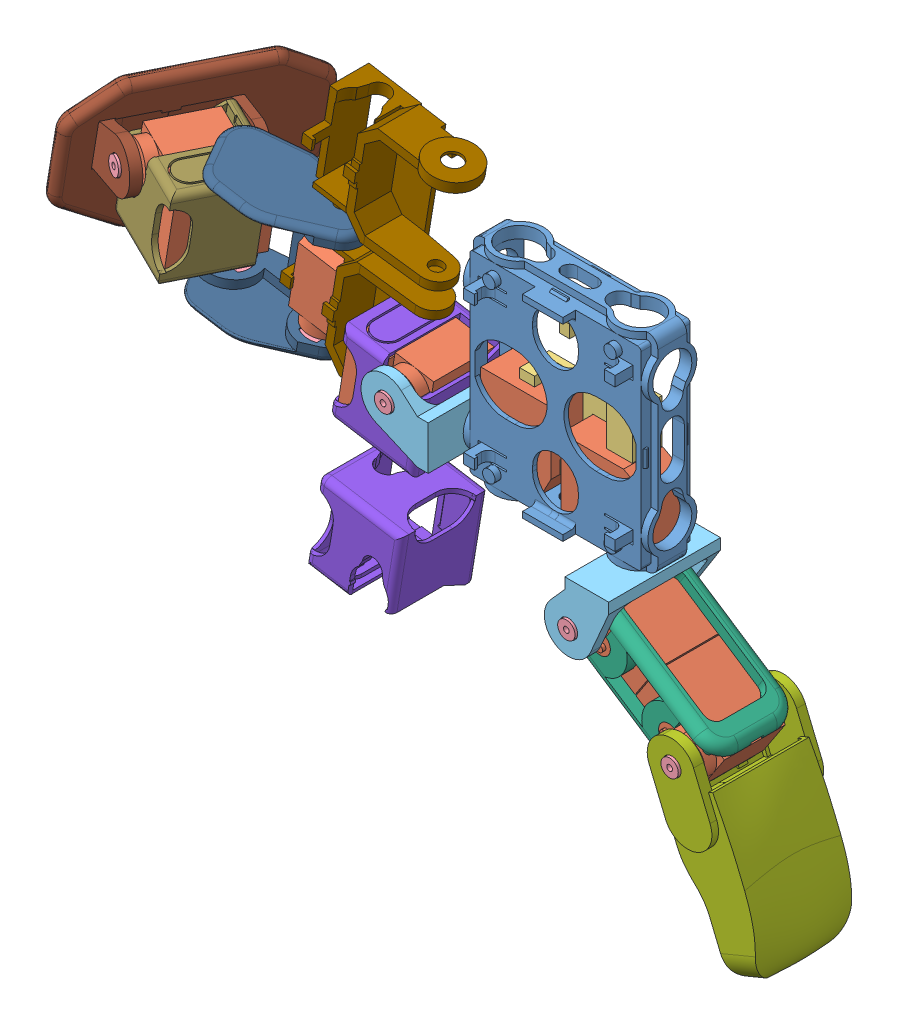
SolidWorks assembly Assem_Body, configuration ﾃﾞﾌｫﾙﾄ. Lengths in mm.
Overall size (223.32 163.88 67.55).
29 component instances, 14 part files, 74 mates.
Components (placement in the parent):
- body_middle-1: body_middle [ﾃﾞﾌｫﾙﾄ] at (-32.055 10.1 -20.8) x (0 -1 0) z (0 0 1) size (61.6 54.8 19.4)
- plen2motor_digital_metalgear-3: plen2motor_digital_metalgear [ﾃﾞﾌｫﾙﾄ] at (-11.955 -23.4 -20.8) x (1 0 0) z (0 1 0) size (23.8 11.6 27.9)
- plen2motor_digital_metalgear-4: plen2motor_digital_metalgear [ﾃﾞﾌｫﾙﾄ] at (-14.955 -18.3 -20.8) x (0 -1 0) z (1 0 0) size (23.8 11.6 27.9)
- PLEN2BaseBoard-1: PLEN2BaseBoard [ﾃﾞﾌｫﾙﾄ] at (-32.055 10.1 -19.3) x (0 -1 0) z (0 0 1) size (54 40 1.6) (hidden)
- body_rear-1: body_rear [Default] at (-39.455 -47.7 -22.3) x (0 1 0) z (0 0 -1) size (61.6 54.8 34) (hidden)
- motor_fix_body-1: motor_fix_body [ﾃﾞﾌｫﾙﾄ] at (-12.155 -23.4 -32.4) x (1 0 0) z (0 0 -1) size (33.46 40 8.8)
- servo_horn_rev1-1: servo_horn_rev1 [Default] at (0.7719 -62.1036 -11.1999) x (-1 0 0) z (0 -1 0) size (10.8 3.5 10.8)
- servo_bracket_type1-1: servo_bracket_type1 [ﾃﾞﾌｫﾙﾄ] at (-51.1552 -22.6 -29.3499) x (0 1 0) z (0 0 -1) size (93.31 19.12 33.2)
- plen2motor_digital_metalgear-5: plen2motor_digital_metalgear [ﾃﾞﾌｫﾙﾄ] at (12.7873 -76.9532 -38.8999) x (-0.835365 0.549695 0) z (0 0 -1) size (23.8 11.6 27.9)
- servo_assem_type1-1: servo_assem_type1 [ﾃﾞﾌｫﾙﾄ] at (36.1079 -85.3557 -18.0999) x (-0.835365 0.549695 0) z (0 0 -1) size (47.9 17.6 27.3)
- plen2motor_digital_metalgear-6: plen2motor_digital_metalgear [ﾃﾞﾌｫﾙﾄ] at (19.4144 -67.4279 -38.8999) x (0.835365 -0.549695 0) z (0 0 -1) size (23.8 11.6 27.9)
- hand_with_bracket-1: hand_with_bracket [ﾃﾞﾌｫﾙﾄ] at (-4.2028 -115.5264 -29.4499) x (-0.923728 -0.383049 0) z (0 0 -1) size (19.58 60.26 33.2)
- servo_horn_rev1-2: servo_horn_rev1 [Default] at (31.4298 -82.2774 -11.1999) x (-0.923728 -0.383049 0) z (0.383049 -0.923728 0) size (10.8 3.5 10.8)
- servo_bracket_type1-2: servo_bracket_type1 [ﾃﾞﾌｫﾙﾄ] at (-14.155 20.9003 -29.3499) x (1 0 0) z (0 0 -1) size (93.31 19.12 33.2)
- servo_horn_rev1-3: servo_horn_rev1 [Default] at (-53.6586 -31.0269 -11.1999) x (1 0 0) z (0 1 0) size (10.8 3.5 10.8)
- servo_assem_type2-1: servo_assem_type2 [ﾃﾞﾌｫﾙﾄ] at (-77.6577 -55.3938 -17.9888) x (0.162468 0.986714 0) z (0 0 -1) size (71.68 25.2 27.6)
- plen2motor_digital_metalgear-7: plen2motor_digital_metalgear [ﾃﾞﾌｫﾙﾄ] at (-62.3384 -48.0427 -38.8999) x (0.162468 0.986714 0) z (0 0 -1) size (23.8 11.6 27.9)
- plen2motor_digital_metalgear-8: plen2motor_digital_metalgear [ﾃﾞﾌｫﾙﾄ] at (-58.6342 -25.5457 -16.0999) x (0 0 -1) z (0.162468 0.986714 0) size (23.8 11.6 27.9)
- servo_bracket_knee-1: servo_bracket_knee [ﾃﾞﾌｫﾙﾄ] at (-49.504 -19.9541 -32.5496) x (0.162468 0.986714 0) z (0 0 -1) size (71 42.95 18.19)
- servo_horn_rev1-4: servo_horn_rev1 [Default] at (-68.8575 -51.9353 -34.2999) x (0.986714 -0.162468 0) z (0 0 1) size (10.8 3.5 10.8)
- plen2motor_digital_metalgear-9: plen2motor_digital_metalgear [ﾃﾞﾌｫﾙﾄ] at (-97.659 -18.8159 -52.7998) x (0 0 1) z (0.162468 0.986714 0) size (23.8 11.6 27.9)
- servo_bracket_shin-1: servo_bracket_shin [ﾃﾞﾌｫﾙﾄ] at (-49.3565 -19.6749 -32.8498) x (0.162468 0.986714 0) z (0 0 -1) size (74.63 42.87 25.65)
- servo_horn_rev1-5: servo_horn_rev1 [Default] at (-96.4365 -47.0902 -34.5998) x (0.986714 -0.162468 0) z (0 0 1) size (10.8 3.5 10.8)
- servo_horn_rev1-6: servo_horn_rev1 [Default] at (-124.1627 -42.5249 -34.6001) x (0.986714 -0.162468 0) z (0 0 1) size (10.8 3.5 10.8)
- plen2motor_digital_metalgear-10: plen2motor_digital_metalgear [ﾃﾞﾌｫﾙﾄ] at (-137.5668 -35.3519 -45.408) x (0.162468 0.986714 0) z (0.371194 -0.061119 -0.926542) size (23.8 11.6 27.9)
- plen2motor_digital_metalgear-11: plen2motor_digital_metalgear [ﾃﾞﾌｫﾙﾄ] at (-121.1155 -14.9537 -15.5552) x (0.371194 -0.061119 -0.926542) z (0.162468 0.986714 0) size (23.8 11.6 27.9)
- foot_with_bracket-1: foot_with_bracket [ﾃﾞﾌｫﾙﾄ] at (-55.2342 -17.2884 -5.1428) x (0.162468 0.986714 0) z (0.371194 -0.061119 -0.926542) size (42.36 22.25 63.87)
- servo_horn_rev1-7: servo_horn_rev1 [Default] at (-139.5894 -16.5738 -17.5608) x (0.162468 0.986714 0) z (-0.914231 0.150534 -0.376192) size (10.8 3.5 10.8)
- servo_assem_type2_mirror-1: servo_assem_type2_mirror [ﾃﾞﾌｫﾙﾄ] at (-151.4617 -31.1497 -16.1294) x (-0.371194 0.061119 0.926542) z (0.162468 0.986714 0) size (27.6 25.2 27.6)
Mates (geometry in assembly coordinates):
- 距離6: distance = 0.2 mm anti-aligned: plane of plen2motor_digital_metalgear-3 through (-11.955 -23.4 -20.8) normal (0 0 1); plane of body_middle-1 through (-26.9398 -16.9 -20.6) normal (0 0 -1)
- 一致10: coincident aligned: plane of body_middle-1 through (15.345 -47.7 -19.3) normal (0 -1 0); plane of plen2motor_digital_metalgear-3 through (6.245 -47.7 -26.6) normal (0 -1 0)
- 距離7: distance = 0.2 mm anti-aligned: plane of plen2motor_digital_metalgear-4 through (-14.955 -18.3 -20.8) normal (0 0 1); plane of body_middle-1 through (-26.9398 -16.9 -20.6) normal (0 0 -1)
- 距離10: distance = 2.1 mm aligned: plane of plen2motor_digital_metalgear-3 through (-11.955 -44.2 -32.4) normal (0 -1 0); plane of plen2motor_digital_metalgear-4 through (-17.7198 -42.1 -32.4) normal (0 -1 0)
- 距離1: distance = 3 mm anti-aligned: plane of plen2motor_digital_metalgear-3 through (-11.955 -23.4 -32.4) normal (-1 0 0); plane of plen2motor_digital_metalgear-4 through (-14.955 -18.3 -32.4) normal (1 0 0)
- 一致24: coincident anti-aligned: plane of body_middle-1 through (-32.055 10.1 -19.3) normal (0 0 1); plane of PLEN2BaseBoard-1 through (-32.055 10.1 -19.3) normal (0 0 -1)
- 一致43: coincident anti-aligned: plane of body_middle-1 through (12.345 10.9 -22.3) normal (0 0 1); plane of body_rear-1 through (-39.455 13.9 -22.3) normal (0 0 -1)
- 一致47: coincident anti-aligned: plane of body_middle-1 through (11.845 10.1 -20.8) normal (-1 0 0); plane of plen2motor_digital_metalgear-3 through (11.845 -26.1649 -32.4) normal (1 0 0)
- 同心円1: concentric anti-aligned: cylinder of plen2motor_digital_metalgear-3 through (6.245 -51.3 -26.6) axis (0 1 0) radius 2; cylinder of servo_bracket_type1-1 through (6.245 -49.299 -26.6) axis (0 -1 0) radius 0.8
- 平行2: parallel anti-aligned: line of body_middle-1 through (15.345 -44.7 -22.3) axis (0 0 -1); line of servo_bracket_type1-1 through (12.745 -52.4997 -37.8999) axis (0 0 1)
- 一致49: coincident anti-aligned: circle of plen2motor_digital_metalgear-3; plane of servo_bracket_type1-1 through (-51.1552 -51.3 -29.3499) normal (0 1 0)
- 同心円2: concentric aligned: cylinder of servo_bracket_type1-1 through (0.7719 -62.1036 -10.2988) axis (0 0 -1) radius 2.75; cylinder of plen2motor_digital_metalgear-5 through (0.7719 -62.1036 -10.9999) axis (0 0 -1) radius 2
- 平行3: parallel anti-aligned: line of servo_horn_rev1-1 through (3.4219 -59.4536 -11.1999) axis (1 0 0); line of servo_bracket_type1-1 through (5.6209 -64.8036 -13.2999) axis (-1 0 0)
- 一致54: coincident anti-aligned: plane of servo_horn_rev1-1 through (0.7719 -62.1036 -11.1999) normal (0 0 1); plane of servo_bracket_type1-1 through (0.7719 -62.1036 -11.1999) normal (0 0 -1)
- 同心円3: concentric aligned: cylinder of servo_horn_rev1-1 through (0.7719 -62.1036 -9.6999) axis (0 0 -1) radius 2.575; cylinder of servo_bracket_type1-1 through (0.7719 -62.1036 -10.2988) axis (0 0 -1) radius 2.75
- 一致55: coincident anti-aligned: plane of servo_horn_rev1-1 through (0.7719 -62.1036 -10.9999) normal (0 0 -1); plane of plen2motor_digital_metalgear-5 through (0.7719 -62.1036 -10.9999) normal (0 0 1)
- 同心円4: concentric anti-aligned: cylinder of servo_bracket_type1-1 through (0.7719 -62.1036 -40.8999) axis (0 0 -1) radius 2; cylinder of servo_assem_type1-1 through (0.7719 -62.1036 -41.8999) axis (0 0 1) radius 2
- 一致56: coincident anti-aligned: plane of plen2motor_digital_metalgear-5 through (19.1638 -67.263 -38.8999) normal (0 0 -1); plane of servo_assem_type1-1 through (-1.919 -66.6104 -38.8999) normal (0 0 1)
- 平行5: parallel aligned: line of plen2motor_digital_metalgear-5 through (12.7873 -76.9532 -38.8999) axis (-0.835365 0.549695 0); line of servo_assem_type1-1 through (24.4824 -84.6489 -36.3999) axis (-0.835365 0.549695 0)
- 一致58: coincident anti-aligned: plane of servo_assem_type1-1 through (26.2506 -78.8693 -18.0999) normal (0 0 -1); plane of plen2motor_digital_metalgear-6 through (13.0379 -77.1181 -18.0999) normal (0 0 1)
- 同心円5: concentric aligned: cylinder of servo_assem_type1-1 through (26.2506 -78.8693 -14.5999) axis (0 0 -1) radius 3; cylinder of plen2motor_digital_metalgear-6 through (26.2506 -78.8693 -14.5999) axis (0 0 -1) radius 3
- 平行6: parallel aligned: line of servo_assem_type1-1 through (9.3684 -57.226 -18.5999) axis (0.835365 -0.549695 0); line of plen2motor_digital_metalgear-6 through (19.4144 -67.4279 -18.0999) axis (0.835365 -0.549695 0)
- 同心円7: concentric aligned: cylinder of hand_with_bracket-1 through (31.4298 -82.2774 -10.3999) axis (0 0 -1) radius 2.7; cylinder of servo_horn_rev1-2 through (31.4298 -82.2774 -9.6999) axis (0 0 -1) radius 2.575
- 一致60: coincident anti-aligned: plane of hand_with_bracket-1 through (31.4298 -82.2774 -11.1999) normal (0 0 -1); plane of servo_horn_rev1-2 through (31.4298 -82.2774 -11.1999) normal (0 0 1)
- 平行7: parallel aligned: line of hand_with_bracket-1 through (32.8896 -78.7491 -13.3999) axis (0.923728 0.383049 0); line of servo_horn_rev1-2 through (32.8626 -78.8145 -13.1999) axis (0.923728 0.383049 0)
- 一致62: coincident anti-aligned: plane of plen2motor_digital_metalgear-6 through (31.4298 -82.2774 -10.9999) normal (0 0 1); plane of servo_horn_rev1-2 through (31.4298 -82.2774 -10.9999) normal (0 0 -1)
- 同心円8: concentric aligned: cylinder of servo_assem_type1-1 through (31.4298 -82.2774 -41.8999) axis (0 0 1) radius 2; cylinder of hand_with_bracket-1 through (31.4298 -82.2774 -42.9999) axis (0 0 1) radius 2
- 同心円9: concentric anti-aligned: cylinder of plen2motor_digital_metalgear-4 through (-42.855 -36.5 -26.6) axis (1 0 0) radius 2; cylinder of servo_bracket_type1-2 through (-43.0547 -36.5 -26.6) axis (-1 0 0) radius 1.5016
- 一致63: coincident anti-aligned: plane of plen2motor_digital_metalgear-4 through (-42.855 -36.5 -26.6) normal (-1 0 0); plane of servo_bracket_type1-2 through (-42.855 20.9003 -29.3499) normal (1 0 0)
- 平行8: parallel anti-aligned: line of body_middle-1 through (-39.455 -44.7 -30.9) axis (0 0 1); line of servo_bracket_type1-2 through (-40.855 -42.9999 -10.2999) axis (0 0 -1)
- 同心円11: concentric aligned: cylinder of servo_bracket_type1-2 through (-53.6586 -31.0269 -10.2988) axis (0 0 -1) radius 2.75; cylinder of servo_horn_rev1-3 through (-53.6586 -31.0269 -9.6999) axis (0 0 -1) radius 2.575
- 一致64: coincident anti-aligned: plane of servo_bracket_type1-2 through (-53.6586 -31.0269 -11.1999) normal (0 0 -1); plane of servo_horn_rev1-3 through (-53.6586 -31.0269 -11.1999) normal (0 0 1)
- 平行9: parallel aligned: line of servo_bracket_type1-2 through (-48.8096 -33.7269 -13.2999) axis (-1 0 0); line of servo_horn_rev1-3 through (-48.9535 -33.6769 -13.1999) axis (-1 0 0)
- 一致65: coincident anti-aligned: plane of servo_assem_type2-1 through (-50.8926 -49.9274 -18.0999) normal (0 0 -1); plane of plen2motor_digital_metalgear-7 through (-50.8926 -49.9274 -18.0999) normal (0 0 1)
- 同心円12: concentric anti-aligned: cylinder of servo_assem_type2-1 through (-54.6659 -37.1445 -43.5282) axis (0 0 1) radius 3; cylinder of plen2motor_digital_metalgear-7 through (-54.6659 -37.1445 -14.5999) axis (0 0 -1) radius 3
- 同心円13: concentric aligned: cylinder of servo_horn_rev1-3 through (-53.6586 -31.0269 -9.6999) axis (0 0 -1) radius 0.85; cylinder of plen2motor_digital_metalgear-7 through (-53.6586 -31.0269 -10.9999) axis (0 0 -1) radius 2
- 一致67: coincident anti-aligned: plane of servo_horn_rev1-3 through (-53.6586 -31.0269 -10.9999) normal (0 0 -1); plane of plen2motor_digital_metalgear-7 through (-53.6586 -31.0269 -10.9999) normal (0 0 1)
- 一致68: coincident anti-aligned: plane of servo_assem_type2-1 through (-62.2108 -46.0368 -36.2894) normal (0.162468 0.986714 0); plane of plen2motor_digital_metalgear-8 through (-73.4594 -44.1847 -16.0999) normal (-0.162468 -0.986714 0)
- 同心円14: concentric anti-aligned: cylinder of servo_assem_type2-1 through (-67.7364 -45.127 -28.0999) axis (-0.162468 -0.986714 0) radius 3; cylinder of plen2motor_digital_metalgear-8 through (-68.3051 -48.5805 -28.0999) axis (0.162468 0.986714 0) radius 3
- 平行12: parallel anti-aligned: line of servo_assem_type2-1 through (-73.0413 -47.8006 -16.5999) axis (0 0 -1); line of plen2motor_digital_metalgear-8 through (-73.4594 -44.1847 -39.8999) axis (0 0 1)
- 同心円15: concentric aligned: cylinder of servo_bracket_knee-1 through (-70.2281 -60.2593 -34.2999) axis (0.162468 0.986714 0) radius 2.7; cylinder of servo_horn_rev1-4 through (-69.1012 -53.4154 -34.2999) axis (0.162468 0.986714 0) radius 2.575
- 一致69: coincident anti-aligned: plane of servo_bracket_knee-1 through (-68.8571 -51.9354 -34.2999) normal (0.162468 0.986714 0); plane of servo_horn_rev1-4 through (-68.8575 -51.9353 -34.2999) normal (-0.162468 -0.986714 0)
- 平行13: parallel aligned: line of servo_bracket_knee-1 through (-65.8356 -50.2033 -31.5999) axis (0.986714 -0.162468 0); line of servo_horn_rev1-4 through (-65.9177 -50.3924 -31.6499) axis (0.986714 -0.162468 0)
- 同心円16: concentric aligned: cylinder of plen2motor_digital_metalgear-8 through (-68.89 -52.1327 -34.2999) axis (0.162468 0.986714 0) radius 2; cylinder of servo_horn_rev1-4 through (-69.1012 -53.4154 -34.2999) axis (0.162468 0.986714 0) radius 0.85
- 一致71: coincident anti-aligned: plane of plen2motor_digital_metalgear-8 through (-68.89 -52.1327 -34.2999) normal (-0.162468 -0.986714 0); plane of servo_horn_rev1-4 through (-68.89 -52.1327 -34.2999) normal (0.162468 0.986714 0)
- 一致72: coincident anti-aligned: plane of servo_bracket_knee-1 through (-95.3154 -40.2819 -33.7998) normal (0.162468 0.986714 0); plane of plen2motor_digital_metalgear-9 through (-89.5925 -41.2242 -52.7998) normal (-0.162468 -0.986714 0)
- 同心円17: concentric anti-aligned: cylinder of servo_bracket_knee-1 through (-95.3154 -40.2819 -40.7998) axis (-0.162468 -0.986714 0) radius 3; cylinder of plen2motor_digital_metalgear-9 through (-95.8841 -43.7354 -40.7998) axis (0.162468 0.986714 0) radius 3
- 平行14: parallel anti-aligned: line of servo_bracket_knee-1 through (-103.5805 -42.4682 -45.3392) axis (0 0 1); line of plen2motor_digital_metalgear-9 through (-101.0384 -39.3396 -28.9998) axis (0 0 -1)
- 同心円18: concentric aligned: cylinder of servo_bracket_shin-1 through (-99.72 -67.0322 -34.5998) axis (0.162468 0.986714 0) radius 2.7; cylinder of servo_horn_rev1-5 through (-96.6802 -48.5703 -34.5998) axis (0.162468 0.986714 0) radius 2.575
- 一致74: coincident anti-aligned: plane of servo_bracket_shin-1 through (-96.4365 -47.0902 -34.5998) normal (0.162468 0.986714 0); plane of servo_horn_rev1-5 through (-96.4365 -47.0902 -34.5998) normal (-0.162468 -0.986714 0)
- 平行15: parallel aligned: line of servo_bracket_shin-1 through (-93.4149 -45.3581 -31.8998) axis (0.986714 -0.162468 0); line of servo_horn_rev1-5 through (-93.4968 -45.5473 -31.9498) axis (0.986714 -0.162468 0)
- 同心円19: concentric aligned: cylinder of plen2motor_digital_metalgear-9 through (-96.469 -47.2876 -34.5998) axis (0.162468 0.986714 0) radius 2; cylinder of servo_horn_rev1-5 through (-96.6802 -48.5703 -34.5998) axis (0.162468 0.986714 0) radius 0.85
- 一致76: coincident anti-aligned: plane of plen2motor_digital_metalgear-9 through (-96.469 -47.2876 -34.5998) normal (-0.162468 -0.986714 0); plane of servo_horn_rev1-5 through (-96.469 -47.2876 -34.5998) normal (0.162468 0.986714 0)
- 同心円20: concentric aligned: cylinder of servo_bracket_shin-1 through (-127.4463 -62.4669 -34.6001) axis (0.162468 0.986714 0) radius 2.7; cylinder of servo_horn_rev1-6 through (-124.4064 -44.005 -34.6001) axis (0.162468 0.986714 0) radius 2.575
- 一致77: coincident anti-aligned: plane of servo_bracket_shin-1 through (-124.1627 -42.5249 -34.6001) normal (0.162468 0.986714 0); plane of servo_horn_rev1-6 through (-124.1627 -42.5249 -34.6001) normal (-0.162468 -0.986714 0)
- 平行16: parallel aligned: line of servo_bracket_shin-1 through (-126.4694 -39.9155 -39.4491) axis (0 0 1); line of servo_horn_rev1-6 through (-126.4526 -40.121 -39.3052) axis (0 0 1)
- 同心円24: concentric aligned: cylinder of servo_horn_rev1-6 through (-124.4064 -44.005 -34.6001) axis (0.162468 0.986714 0) radius 0.85; cylinder of plen2motor_digital_metalgear-11 through (-124.1952 -42.7223 -34.6001) axis (0.162468 0.986714 0) radius 2
- 平行19: parallel aligned: line of servo_assem_type2-1 through (-51.798 -49.2715 -40.3999) axis (-0.986714 0.162468 0); line of servo_bracket_knee-1 through (-77.9995 -50.8347 -41.2996) axis (-0.986714 0.162468 0)
- 平行20: parallel aligned: line of servo_bracket_knee-1 through (-77.9995 -50.8347 -41.2996) axis (-0.986714 0.162468 0); line of servo_bracket_shin-1 through (-106.1956 -45.9901 -44.347) axis (-0.986714 0.162468 0)
- 一致83: coincident anti-aligned: plane of servo_horn_rev1-6 through (-124.1952 -42.7223 -34.6001) normal (0.162468 0.986714 0); circle of plen2motor_digital_metalgear-11
- 同心円25: concentric aligned: cylinder of foot_with_bracket-1 through (-139.9234 -16.5188 -16.727) axis (0.371194 -0.061119 -0.926542) radius 2.75; cylinder of servo_horn_rev1-7 through (-140.1462 -16.4821 -16.171) axis (0.371194 -0.061119 -0.926542) radius 2.575
- 一致84: coincident anti-aligned: plane of foot_with_bracket-1 through (-139.5897 -16.5736 -17.561) normal (0.371194 -0.061119 -0.926542); plane of servo_horn_rev1-7 through (-139.5894 -16.5738 -17.5608) normal (-0.371194 0.061119 0.926542)
- 平行22: parallel aligned: line of foot_with_bracket-1 through (-136.7804 -19.7725 -18.491) axis (-0.162468 -0.986714 0); line of servo_horn_rev1-7 through (-136.8548 -19.7098 -18.417) axis (-0.162468 -0.986714 0)
- 同心円26: concentric aligned: cylinder of plen2motor_digital_metalgear-10 through (-139.6636 -16.5616 -17.3755) axis (0.371194 -0.061119 -0.926542) radius 2; cylinder of servo_horn_rev1-7 through (-140.1462 -16.4821 -16.171) axis (0.371194 -0.061119 -0.926542) radius 0.85
- 一致86: coincident anti-aligned: plane of plen2motor_digital_metalgear-10 through (-139.6636 -16.5616 -17.3755) normal (-0.371194 0.061119 0.926542); plane of servo_horn_rev1-7 through (-139.6636 -16.5616 -17.3755) normal (0.371194 -0.061119 -0.926542)
- 平行25: parallel aligned: line of servo_assem_type2-1 through (-50.1495 -51.5699 -38.3999) axis (0.162468 0.986714 0); line of plen2motor_digital_metalgear-7 through (-50.8926 -49.9274 -38.8999) axis (0.162468 0.986714 0)
- 平行26: parallel aligned: line of plen2motor_digital_metalgear-10 through (-145.2876 -34.0806 -26.1359) axis (0.371194 -0.061119 -0.926542); line of servo_assem_type2_mirror-1 through (-138.5845 -36.7045 -30.1848) axis (0.371194 -0.061119 -0.926542)
- 一致88: coincident anti-aligned: plane of plen2motor_digital_metalgear-10 through (-134.6825 -35.8268 -21.7721) normal (-0.371194 0.061119 0.926542); plane of servo_assem_type2_mirror-1 through (-131.5852 -15.8755 -21.8473) normal (0.371194 -0.061119 -0.926542)
- 同心円28: concentric anti-aligned: cylinder of plen2motor_digital_metalgear-10 through (-139.3346 -22.8992 -20.7111) axis (0.371194 -0.061119 -0.926542) radius 3; cylinder of servo_assem_type2_mirror-1 through (-138.0354 -23.1132 -23.954) axis (-0.371194 0.061119 0.926542) radius 3
- 平行28: parallel anti-aligned: line of foot_with_bracket-1 through (-138.6104 -27.0218 -51.5022) axis (0.162468 0.986714 0); line of servo_assem_type2_mirror-1 through (-134.3013 -13.2899 -47.174) axis (-0.162468 -0.986714 0)
- 平行29: parallel anti-aligned: line of plen2motor_digital_metalgear-10 through (-137.5668 -35.3519 -45.408) axis (0.162468 0.986714 0); line of servo_assem_type2_mirror-1 through (-134.3013 -13.2899 -47.174) axis (-0.162468 -0.986714 0)
- 同心円29: concentric anti-aligned: cylinder of plen2motor_digital_metalgear-11 through (-125.9117 -38.7912 -28.8556) axis (0.162468 0.986714 0) radius 3; cylinder of servo_assem_type2_mirror-1 through (-121.2118 -10.2472 -28.8556) axis (-0.162468 -0.986714 0) radius 3
- 一致89: coincident anti-aligned: plane of plen2motor_digital_metalgear-11 through (-135.1 -33.7312 -19.919) normal (-0.162468 -0.986714 0); plane of servo_assem_type2_mirror-1 through (-124.4949 -35.4773 -15.5552) normal (0.162468 0.986714 0)
- 平行30: parallel aligned: line of plen2motor_digital_metalgear-11 through (-115.6605 -36.932 -37.6068) axis (-0.371194 0.061119 0.926542); line of servo_assem_type2_mirror-1 through (-116.1406 -38.3731 -34.3584) axis (-0.371194 0.061119 0.926542)
